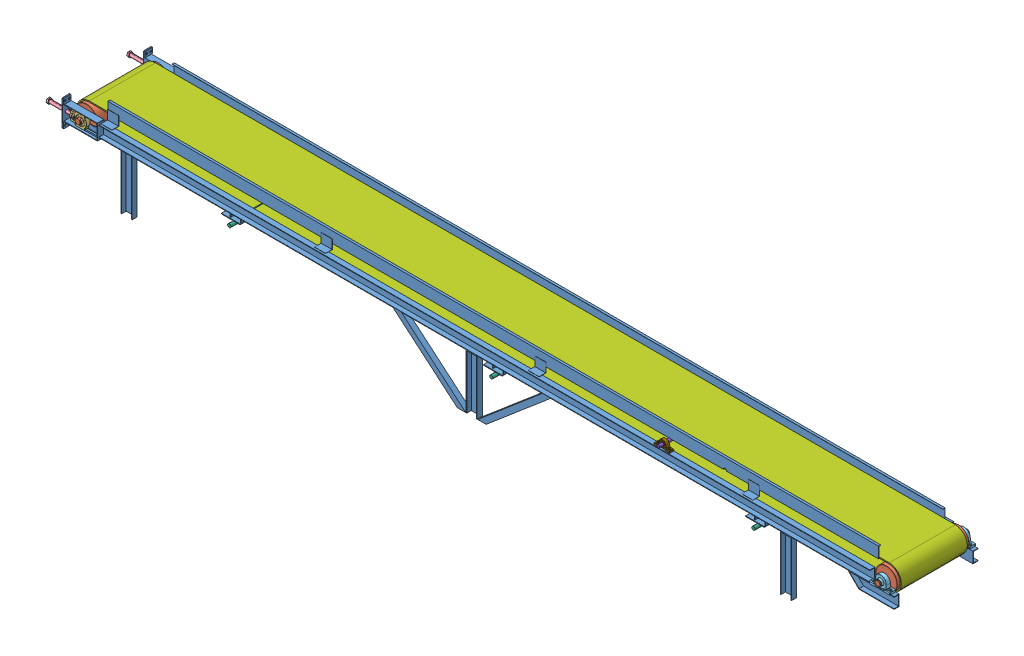
SolidWorks assembly nastro_modificato, configuration Default. Lengths in mm.
Overall size (7695.09 749.36 819.77).
41 component instances, 11 part files, 22 mates.
Components (placement in the parent):
- nastrodx-1: nastrodx [Default] at (-6824.9441 -3222.9182 -381) x (1 -0.000207 -0.000489) z (0.000489 0.000382 1) size (7694.54 747.46 815.72)
  - C-channel -b-up-2: C-channel -b-up [Default<As Machined>] at (4036.4781 3775.6231 338.4141) x (0.000207 -1 -0.000382) z (-1 -0.000206 -0.000489) size (1248 810 7547.03)
  - roller-belt-Motor-up-1: roller-belt-Motor-up [Default] at (7631.6404 3780.4929 5.1727) x (0.000489 0.000382 -1) z (1 0 0.000489) size (812 200 200)
  - Uct 209-up-1: Uct 209-up [Default] at (366.4634 3774.8539 367.6204) x (1 0.000206 0.000489) z (-0.000489 -0.000382 1) size (144 117 54.7)
  - Extender-screw-up-1: Extender-screw-up [Default] at (302.9634 3774.8408 367.5894) x (0.000489 0 -1) z (-1 -0.000206 -0.000489) size (46.02 42.15 250)
  - Bearing-b_P209_45-up-1: Bearing-b_P209_45-up [Default] at (7631.4747 3726.3547 367.152) x (1 0.000206 0.000489) z (-0.000489 -0.000382 1) size (190 108 62)
  - upper-roller-inside-up-1: upper-roller-inside-up [Default] at (6502.8061 3649.373 4.571) x (1 0 0.000489) z (-0.000489 -0.000382 1) size (50 50 810)
  - Bearing-b_P209_45-up-2: Bearing-b_P209_45-up [Default] at (7631.8285 3726.6312 -356.8478) x (-1 -0.000206 -0.000489) z (0.000489 0.000382 -1) size (190 108 62)
  - Uct 209-up-2: Uct 209-up [Default] at (366.8211 3775.1334 -364.3794) x (1 0.000206 0.000489) z (0.000489 0.000382 -1) size (144 117 54.7)
  - Extender-screw-up-2: Extender-screw-up [Default] at (303.3211 3775.1203 -364.4105) x (0.000489 0.000764 -1) z (-1 -0.000206 -0.000489) size (46.02 42.15 250)
  - upper-roller-inside-up-2: upper-roller-inside-up [Default] at (4122.8064 3648.8818 3.4078) x (1 0 0.000489) z (-0.000489 -0.000382 1) size (50 50 810)
  - upper-roller-inside-up-3: upper-roller-inside-up [Default] at (1742.8067 3648.3906 2.2446) x (1 0 0.000489) z (-0.000489 -0.000382 1) size (50 50 810)
  - Belt-1: Belt [Default] at (4036.6418 3775.751 3.4142) x (-0.000207 1 0.000382) z (0.000489 0.000382 -1) size (228 7489 600)
  - roller-upper-2: roller-upper [Default] at (5639.6653 3862.5818 4.2307) x (1 0 0.000489) z (-0.000489 -0.000382 1) size (29 29 810)
  - UCP-205-1: UCP-205 [Default] at (5639.4923 3862.4467 358.2306) x (0.000489 0.000382 -1) z (1 0 0.000489) size (38.7 70 140)
  - UCP-205-2: UCP-205 [Default] at (5639.8383 3862.717 -349.7693) x (0.000489 0.000382 -1) z (1 0.000206 0.000489) size (38.7 70 140)
  - roller-belt-Motor-up-2: roller-belt-Motor-up [Default] at (366.6414 3778.9936 1.622) x (0.000489 0.000382 -1) z (1 0 0.000489) size (812 200 200)
- vassoioX1_componibile-1: vassoioX1_componibile [Default] at (-6928 1105 -1094) x (0 0 1) z (0 1 0) size (500.32 200 150) (hidden)
- vassoioX2_componibile-1: vassoioX2_componibile [Default] at (-6942 1105 -689.3) x (0 0 -1) z (0 1 0) size (294.6 172 67) (hidden)
- vassoioX1_componibile-2: vassoioX1_componibile [Default] at (-3928 1105 510) x (0 0 -1) z (0 1 0) size (500.32 200 150) (hidden)
- vassoioX2_componibile-2: vassoioX2_componibile [Default] at (-3942 1105 105.3) x (0 0 1) z (0 1 0) size (294.6 172 67) (hidden)
- vassoioX1_componibile-3: vassoioX1_componibile [Default] at (-3743 1105 510) x (0 0 -1) z (0 1 0) size (500.32 200 150) (hidden)
- vassoioX1_componibile-4: vassoioX1_componibile [Default] at (-3558 1105 510) x (0 0 -1) z (0 1 0) size (500.32 200 150) (hidden)
- vassoioX1_componibile-5: vassoioX1_componibile [Default] at (-3373 1105 510) x (0 0 -1) z (0 1 0) size (500.32 200 150) (hidden)
- vassoioX1_componibile-6: vassoioX1_componibile [Default] at (-3188 1105 510) x (0 0 -1) z (0 1 0) size (500.32 200 150) (hidden)
- vassoioX1_componibile-7: vassoioX1_componibile [Default] at (-3003 1105 510) x (0 0 -1) z (0 1 0) size (500.32 200 150) (hidden)
- vassoioX1_componibile-8: vassoioX1_componibile [Default] at (-6743 1105 -1094) x (0 0 1) z (0 1 0) size (500.32 200 150) (hidden)
- vassoioX1_componibile-9: vassoioX1_componibile [Default] at (-6558 1105 -1094) x (0 0 1) z (0 1 0) size (500.32 200 150) (hidden)
- vassoioX1_componibile-10: vassoioX1_componibile [Default] at (-6373 1105 -1094) x (0 0 1) z (0 1 0) size (500.32 200 150) (hidden)
- vassoioX1_componibile-11: vassoioX1_componibile [Default] at (-6188 1105 -1094) x (0 0 1) z (0 1 0) size (500.32 200 150) (hidden)
- vassoioX1_componibile-12: vassoioX1_componibile [Default] at (-6003 1105 -1094) x (0 0 1) z (0 1 0) size (500.32 200 150) (hidden)
- vassoioX2_componibile-3: vassoioX2_componibile [Default] at (-6767 1105 -689.3) x (0 0 -1) z (0 1 0) size (294.6 172 67) (hidden)
- vassoioX2_componibile-4: vassoioX2_componibile [Default] at (-6592 1105 -689.3) x (0 0 -1) z (0 1 0) size (294.6 172 67) (hidden)
- vassoioX2_componibile-5: vassoioX2_componibile [Default] at (-6417 1105 -689.3) x (0 0 -1) z (0 1 0) size (294.6 172 67) (hidden)
- vassoioX2_componibile-6: vassoioX2_componibile [Default] at (-6242 1105 -689.3) x (0 0 -1) z (0 1 0) size (294.6 172 67) (hidden)
- vassoioX2_componibile-7: vassoioX2_componibile [Default] at (-6067 1105 -689.3) x (0 0 -1) z (0 1 0) size (294.6 172 67) (hidden)
- vassoioX2_componibile-8: vassoioX2_componibile [Default] at (-3767 1105 105.3) x (0 0 1) z (0 1 0) size (294.6 172 67) (hidden)
- vassoioX2_componibile-9: vassoioX2_componibile [Default] at (-3592 1105 105.3) x (0 0 1) z (0 1 0) size (294.6 172 67) (hidden)
- vassoioX2_componibile-10: vassoioX2_componibile [Default] at (-3417 1105 105.3) x (0 0 1) z (0 1 0) size (294.6 172 67) (hidden)
- vassoioX2_componibile-11: vassoioX2_componibile [Default] at (-3242 1105 105.3) x (0 0 1) z (0 1 0) size (294.6 172 67) (hidden)
- vassoioX2_componibile-12: vassoioX2_componibile [Default] at (-3067 1105 105.3) x (0 0 1) z (0 1 0) size (294.6 172 67) (hidden)
Mates (geometry in assembly coordinates):
- Coincidente2: coincident: plane of assembly through (0 0 0) normal (1 0 0); plane of nastrodx-1/C-channel -b-up-2 through (0 -491.7553 -827.8034) normal (1 0 0); plane of assembly
- Coincidente3: coincident aligned: plane of nastrodx-1/C-channel -b-up-2 through (-2787.522 552 0) normal (0 0 1)
- Coincidente4: coincident anti-aligned: plane of nastrodx-1/C-channel -b-up-2 through (-2153.2153 -600.918 -1270) normal (-1 0.000207 0); plane of nastrodx1-1/C-channel -b-up1-2 through (-2153.2154 -601.3311 -1270) normal (1 -0.000207 0)
- Coincidente5: coincident aligned: plane of nastrodx-1/C-channel -b-up-2 through (-6287.522 507 -41) normal (0 1 0); plane of nastrodx1-1/C-channel -b-up1-2 through (-7787.5221 507 -41) normal (0 1 0)
- Coincidente6: coincident aligned: plane of nastrodx-1/C-channel -b-up-2 through (-6287.522 597 -41) normal (0 0 1); plane of nastrodx1-1/C-channel -b-up1-2 through (-7787.5221 597 -41) normal (0 0 1)
- Coincidente8: coincident: plane of assembly through (0 0 0) normal (0 1 0); plane of nastrodx-1/C-channel -b-up-2 through (-7826.508 0 -1079) normal (0 -1 0); plane of assembly
- SulPosto1: in place: plane of ? through (0 0 0) normal (0 1 0); moOrthogonalPlaneRef_w of ? through (0 0 0) normal (0 0 -1); plane of ? through (0 0 0) normal (1 0 0); unknown of ?
- Coincidente9: coincident aligned: 
- Coincidente10: coincident aligned: plane of Parte1^nastro_modificato-1 through (0 0 0) normal (0 0 -1)
- Coincidente11: coincident anti-aligned: plane of Parte1^nastro_modificato-1 through (0 0 0) normal (1 0 0)
- Coincidente12: coincident anti-aligned: plane of Parte1^nastro_modificato-1 through (-1028 1105 -292) normal (0 1 0); plane of vassoioX1_componibile-1 through (-6928 1105 -1094) normal (0 -1 0)
- Coincidente13: coincident anti-aligned: plane of Parte1^nastro_modificato-1 through (-1028 1100 -1344) normal (0 0 1); plane of vassoioX1_componibile-1 through (-6828 1108 -1344) normal (0 0 -1)
- Coincidente14: coincident anti-aligned: plane of Parte1^nastro_modificato-1 through (-7028 1100 -542) normal (0 0 -1); plane of vassoioX2_componibile-1 through (-7028 1115 -542) normal (0 0 1)
- Coincidente15: coincident anti-aligned: plane of Parte1^nastro_modificato-1 through (-1028 1105 -292) normal (0 1 0); plane of vassoioX2_componibile-1 through (-6942 1105 -689.3) normal (0 -1 0)
- Coincidente16: coincident anti-aligned: plane of Parte1^nastro_modificato-1 through (-7028 1100 -1344) normal (1 0 0); plane of vassoioX2_componibile-1 through (-7028 1115 -542) normal (-1 0 0)
- Coincidente17: coincident anti-aligned: plane of Parte1^nastro_modificato-1 through (-7028 1100 -1344) normal (1 0 0); plane of vassoioX1_componibile-1 through (-7028 1108 -1344) normal (-1 0 0)
- Coincidente18: coincident anti-aligned: plane of Parte1^nastro_modificato-1 through (-1028 1105 -292) normal (0 1 0); plane of vassoioX1_componibile-2 through (-3928 1105 510) normal (0 -1 0)
- Coincidente19: coincident anti-aligned: plane of Parte1^nastro_modificato-1 through (-4028 1100 760) normal (0 0 -1); plane of vassoioX1_componibile-2 through (-4028 1108 760) normal (0 0 1)
- Coincidente20: coincident anti-aligned: plane of Parte1^nastro_modificato-1 through (-4028 1100 -42) normal (1 0 0); plane of vassoioX1_componibile-2 through (-4028 1108 760) normal (-1 0 0)
- Coincidente21: coincident anti-aligned: plane of Parte1^nastro_modificato-1 through (-1028 1105 -292) normal (0 1 0); plane of vassoioX2_componibile-2 through (-3942 1105 105.3) normal (0 -1 0)
- Coincidente22: coincident anti-aligned: plane of Parte1^nastro_modificato-1 through (-1028 1100 -42) normal (0 0 1); plane of vassoioX2_componibile-2 through (-3856 1115 -42) normal (0 0 -1)
- Coincidente23: coincident anti-aligned: plane of Parte1^nastro_modificato-1 through (-4028 1100 -42) normal (1 0 0); plane of vassoioX2_componibile-2 through (-4028 1115 -42) normal (-1 0 0)
